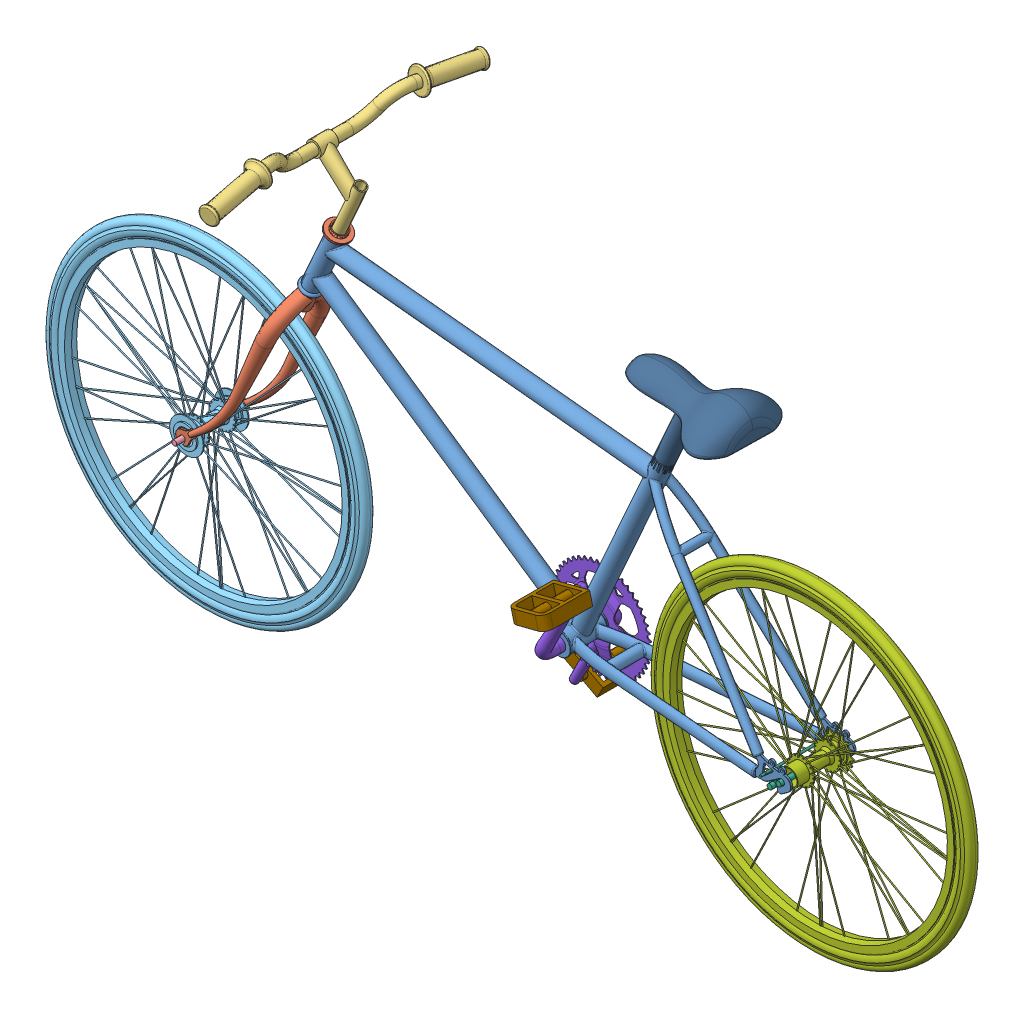
SolidWorks assembly bici, configuration Predeterminado. Lengths in mm.
Overall size (1933.09 1072.61 543.01).
11 component instances, 10 part files, 21 mates.
Components (placement in the parent):
- cuadro-1: cuadro [Predeterminado] at (199.6567 124.6974 1021.1992) x (0 0 1) z (-1 0 0) size (139.46 474.16 1021.2)
- soporte1-1: soporte1 [Predeterminado] at (-422.0302 -213.5231 1021.1992) x (0 0 1) z (-1 0 0) size (132.09 475.77 286.91)
- manubrio-1: manubrio [Predeterminado] at (-393.5586 139.4524 1021.1992) x (0 0 1) z (-1 0 0) size (543.01 289.12 100.53)
- bara_delantera-1: bara_delantera [Predeterminado] at (-677.0302 -226.8231 1091.1992) x (0 0 -1) z (0 -1 0) size (140 10 10)
- llanta_delantera-1: llanta_delantera [Predeterminado] at (-677.0302 -226.8231 1022.1992) x (0 0 -1) z (1 0 0) size (98 630.55 630.55)
- barra_ilse-3: barra_ilse [Predeterminado] at (505.9166 -213.4411 961.0992) x (0 0 1) z (-0.8351 0.550098 0) size (140 30.58 34.04)
- llanta_atras-2: llanta_atras [Predeterminado] at (505.9166 -213.4411 1020.1992) x (0 0 1) z (-0.845764 0.533557 0) size (98 630.55 630.55)
- estrella-2: estrella [Predeterminado] at (45.0967 -222.4499 980.1992) x (0 0 1) z (0.883149 -0.469092 0) size (306 370 193.65)
- pedal-1: pedal [Predeterminado] at (-37.5807 -378.105 883.0392) x (0.883149 -0.469092 0) z (0 0 -1) size (73 25 102)
- pedal-2: pedal [Predeterminado] at (127.7742 -66.7948 1161.0392) x (0.968503 0.249002 0) z (0 0 1) size (73 25 102)
- asiento-1: asiento [Predeterminado] at (268.6442 275.0216 1021.2274) x (0.013684 -0.006093 -0.999888) z (0.997468 -0.069714 0.014076) size (175.81 198.23 238.77)
Mates (geometry in assembly coordinates):
- Coincidente4: coincident anti-aligned: plane of cuadro-1 through (-445.282 230.2129 1021.1992) normal (0.406737 0.913545 0); plane of soporte1-1 through (-443.4549 229.3995 1021.1992) normal (-0.406737 -0.913545 0)
- Concéntrica2: concentric aligned: cylinder of soporte1-1 through (-495.6495 65.4552 1021.1992) axis (0.406737 0.913545 0) radius 12.5; cylinder of manubrio-1 through (-462.7038 139.4524 1021.1992) axis (0.406737 0.913545 0) radius 10.5
- Distancia1: distance = 100 mm aligned: plane of soporte1-1 through (-422.0302 230.8069 1021.1992) normal (0.406737 0.913545 0); plane of manubrio-1 through (-381.3565 322.1615 1021.1992) normal (0.406737 0.913545 0)
- Coincidente6: coincident aligned: plane of soporte1-1 through (-422.0302 -213.5231 1021.1992) normal (0 0 1); plane of manubrio-1 through (-393.5586 139.4524 1021.1992) normal (0 0 1)
- Concéntrica3: concentric anti-aligned: cylinder of soporte1-1 through (-677.0302 -226.8231 1075.1992) axis (0 0 -1) radius 5; cylinder of bara_delantera-1 through (-677.0302 -226.8231 951.1992) axis (0 0 1) radius 5
- Ancho1: width anti-aligned: plane of bara_delantera-1 through (-677.0302 -226.8231 1091.1992) normal (0 0 1); plane of bara_delantera-1 through (-677.0302 -226.8231 951.1992) normal (0 0 -1); plane of soporte1-1 through (-673.2764 -236.3932 967.1992) normal (0 0 -1); plane of soporte1-1 through (-673.2764 -236.3932 1075.1992) normal (0 0 1)
- Concéntrica4: concentric aligned: cylinder of bara_delantera-1 through (-677.0302 -226.8231 951.1992) axis (0 0 1) radius 5; cylinder of llanta_delantera-1 through (-677.0302 -226.8231 1054.2609) axis (0 0 1) radius 10
- Ancho2: width anti-aligned: plane of llanta_delantera-1 through (-677.0302 -211.3231 1070.1992) normal (0 0 1); plane of llanta_delantera-1 through (-677.0302 -211.3231 972.1992) normal (0 0 -1); plane of soporte1-1 through (-673.2764 -236.3932 1071.1992) normal (0 0 -1); plane of soporte1-1 through (-673.2764 -236.3932 971.1992) normal (0 0 1)
- Concéntrica12: concentric aligned: cylinder of cuadro-1 through (505.9166 -213.4411 1085.1992) axis (0 0 -1) radius 5.5; cylinder of barra_ilse-3 through (505.9166 -213.4411 1081.2992) axis (0 0 -1) radius 5
- Ancho6: width anti-aligned: plane of barra_ilse-3 through (505.9166 -213.4411 1091.1992) normal (0 0 1); plane of barra_ilse-3 through (505.9166 -213.4411 951.1992) normal (0 0 -1); plane of cuadro-1 through (448.3301 -205.9175 957.1992) normal (0 0 -1); plane of cuadro-1 through (448.3301 -205.9175 1085.1992) normal (0 0 1)
- Concéntrica13: concentric anti-aligned: cylinder of cuadro-1 through (470.9177 -217.4246 1085.1992) axis (0 0 -1) radius 2; cylinder of barra_ilse-3 through (470.918 -217.4246 959.0992) axis (0 0 1) radius 2
- Concéntrica14: concentric aligned: cylinder of barra_ilse-3 through (505.9166 -213.4411 1081.2992) axis (0 0 -1) radius 5; cylinder of llanta_atras-2 through (505.9166 -213.4411 988.1375) axis (0 0 -1) radius 10
- Ancho7: width anti-aligned: plane of llanta_atras-2 through (514.1867 -200.3317 1070.1992) normal (0 0 1); plane of llanta_atras-2 through (514.1867 -200.3317 972.1992) normal (0 0 -1); plane of cuadro-1 through (448.3301 -205.9175 1081.1992) normal (0 0 -1); plane of cuadro-1 through (448.3301 -205.9175 961.1992) normal (0 0 1)
- Concéntrica15: concentric aligned: cylinder of cuadro-1 through (45.0967 -222.4499 1059.1992) axis (0 0 -1) radius 12.5; cylinder of estrella-2 through (45.0967 -222.4499 974.5392) axis (0 0 -1) radius 12.5
- Coincidente7: coincident aligned: plane of llanta_atras-2 through (523.5239 -185.5309 975.1992) normal (0 0 -1); plane of estrella-2 through (14.8581 -279.3796 975.1992) normal (0 0 -1)
- Concéntrica16: concentric aligned: cylinder of estrella-2 through (-37.5807 -378.105 869.0392) axis (0 0 1) radius 5; cylinder of pedal-1 through (-37.5807 -378.105 830.3971) axis (0 0 1) radius 5
- Coincidente8: coincident anti-aligned: plane of estrella-2 through (-48.3089 -382.3143 939.0392) normal (0 0 -1); plane of pedal-1 through (-37.5807 -378.105 939.0392) normal (0 0 1)
- Paralelo4: parallel anti-aligned: plane of estrella-2 through (-40.0998 -366.8592 939.0392) normal (-0.469092 -0.883149 0); plane of pedal-1 through (-12.7294 -377.1511 852.0392) normal (0.469092 0.883149 0)
- Coincidente10: coincident aligned: cylinder of estrella-2 through (127.7742 -66.7948 1175.0392) axis (0 0 -1) radius 5; circle of pedal-2
- Coincidente11: coincident anti-aligned: plane of estrella-2 through (125.2552 -55.5491 1105.0392) normal (0 0 1); plane of pedal-2 through (127.7742 -66.7948 1105.0392) normal (0 0 -1)
- Concéntrica17: concentric anti-aligned: cylinder of cuadro-1 through (45.0967 -222.4499 1021.1992) axis (0.406737 0.913545 0) radius 14; cylinder of asiento-1 through (275.1291 294.2113 1021.1992) axis (-0.406737 -0.913545 0) radius 16
